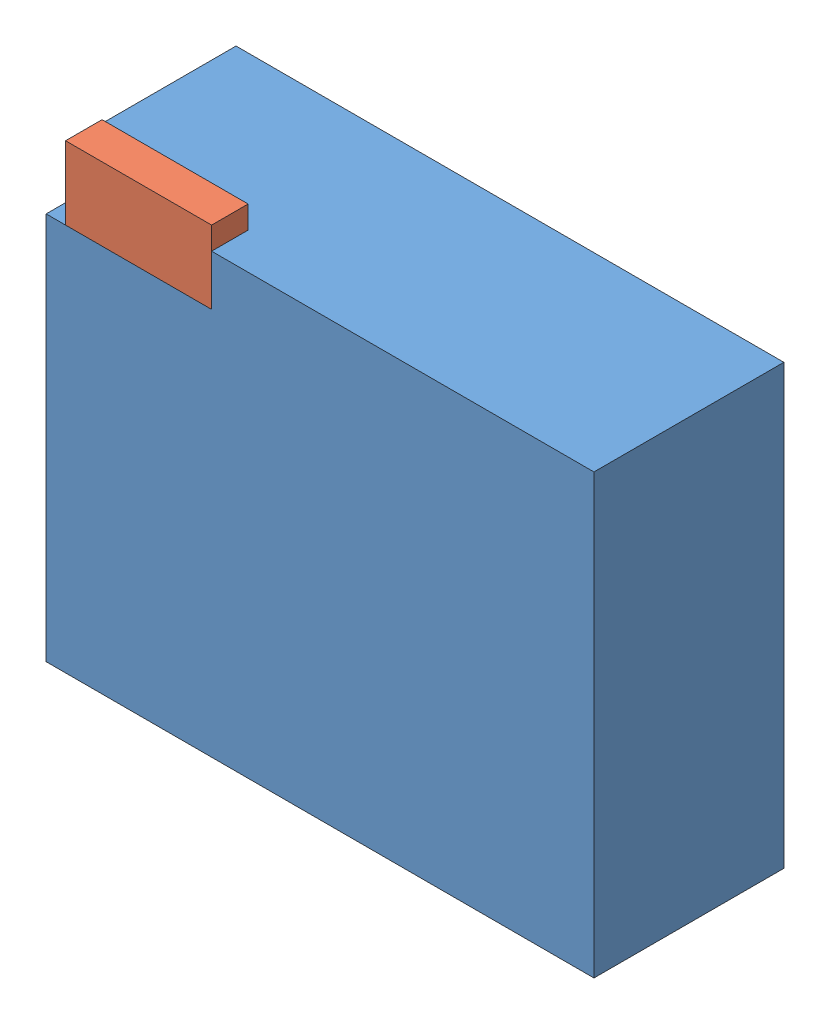
SolidWorks assembly Złożenie1, configuration Domyślna. Lengths in mm.
Overall size (75 63.1 26).
2 component instances, 2 part files, 3 mates.
Components (placement in the parent):
- Część1-1: Część1 [Domyślna] at (-70.6903 33.5963 -13) size (75 60 26)
- Część2-1: Część2 [Domyślna] at (-68.0343 26.6935 8) size (20 10 5)
Mates (geometry in assembly coordinates):
- Wspólnie1: coincident: plane of Część1-1 through (-70.6903 26.6935 8) normal (0 1 0); plane of Część2-1 through (-68.0343 26.6935 13) normal (0 -1 0)
- Wspólnie2: coincident: plane of Część1-1 through (-70.6903 33.5963 13) normal (0 0 1); plane of Część2-1 through (-68.0343 26.6935 13) normal (0 0 1)
- Wspólnie3: coincident: plane of Część1-1 through (-48.0343 33.5963 8) normal (-1 0 0); plane of Część2-1 through (-48.0343 26.6935 13) normal (1 0 0)
